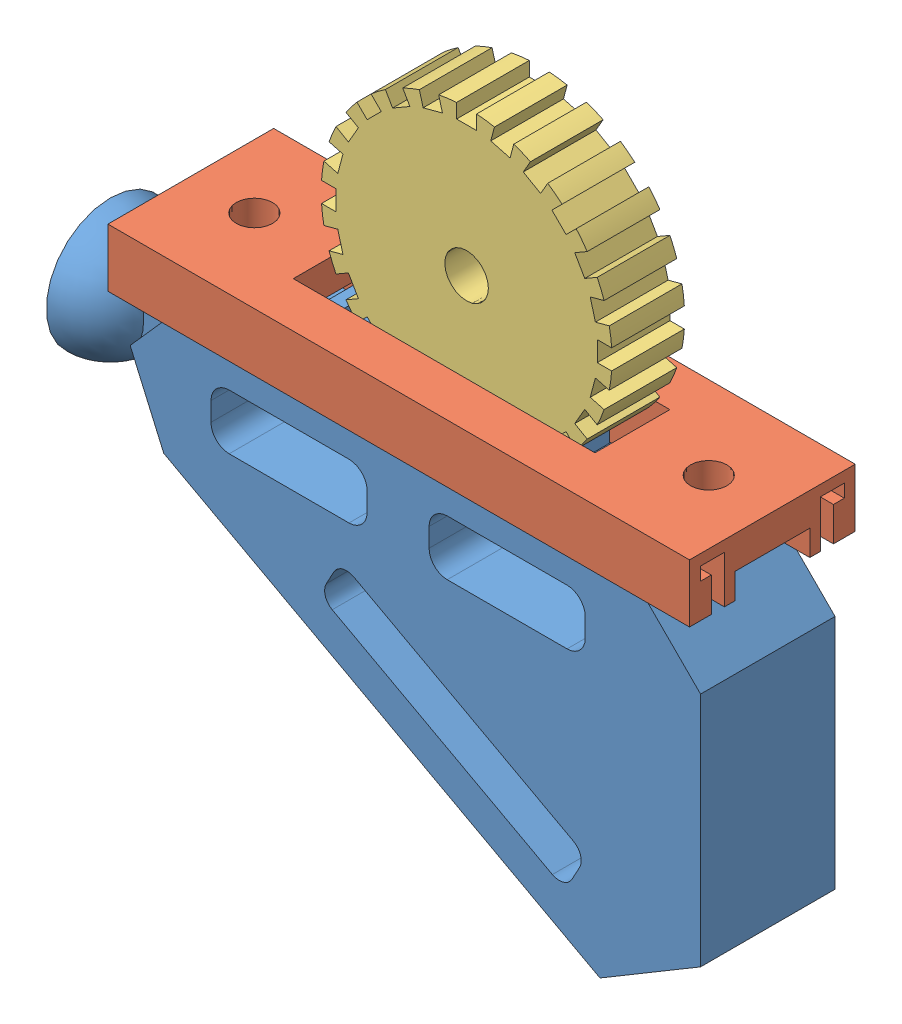
SolidWorks assembly TeamProject_RS_RetractingLegAssembly, configuration Default. Lengths in mm.
Overall size (182.12 180.09 45.6).
3 component instances, 3 part files, 6 mates.
Components (placement in the parent):
- TeamProject_RS_LegMount-1: TeamProject_RS_LegMount [Default] at (126.7077 118.5254 127.4131) size (180.86 113.24 39)
- TeamProject_RS_Rail-1: TeamProject_RS_Rail [Default] at (146.7077 137.2753 129.1131) x (0 0 1) z (-1 0 0) size (45.6 16 160)
- TeamProject_RS_Gear-1: TeamProject_RS_Gear [Default] at (72.2827 177.2253 135.6131) size (79.81 79.81 20)
Mates (geometry in assembly coordinates):
- ProfileCenter1: profile center anti-aligned: plane of TeamProject_RS_Rail-1 through (-13.2923 150.2753 165.7131) normal (0 -1 0); plane of TeamProject_RS_LegMount-1 through (6.7077 150.2753 165.4131) normal (0 1 0)
- Coincident3: coincident anti-aligned: plane of TeamProject_RS_Rail-1 through (-13.2923 137.2753 135.6131) normal (0 0 1); plane of TeamProject_RS_Gear-1 through (72.2827 177.2253 135.6131) normal (0 0 -1)
- Coincident4: coincident anti-aligned: plane of TeamProject_RS_LegMount-1 through (126.7077 141.2753 127.4131) normal (0 1 0); plane of TeamProject_RS_Gear-1 through (69.5327 141.2753 165.4231) normal (0 -1 0)
- Tangent1: tangent aligned: cylinder of TeamProject_RS_Gear-1 through (72.2827 177.2253 155.6131) axis (0 0 -1) radius 40; plane of TeamProject_RS_LegMount-1 through (32.2827 141.2753 164.4131) normal (-1 0 0)
- Tangent2: tangent aligned: plane of TeamProject_RS_LegMount-2 through (-94.7236 340.2796 348.8641) normal (-1 0 0); cylinder of TeamProject_RS_Gear-2 through (-54.7236 376.2296 340.0641) axis (0 0 -1) radius 40
- Coincident7: coincident anti-aligned: plane of TeamProject_RS_LegMount-2 through (-0.2986 340.2796 311.8641) normal (0 1 0); plane of TeamProject_RS_Gear-2 through (-57.4736 340.2796 349.8741) normal (0 -1 0)
